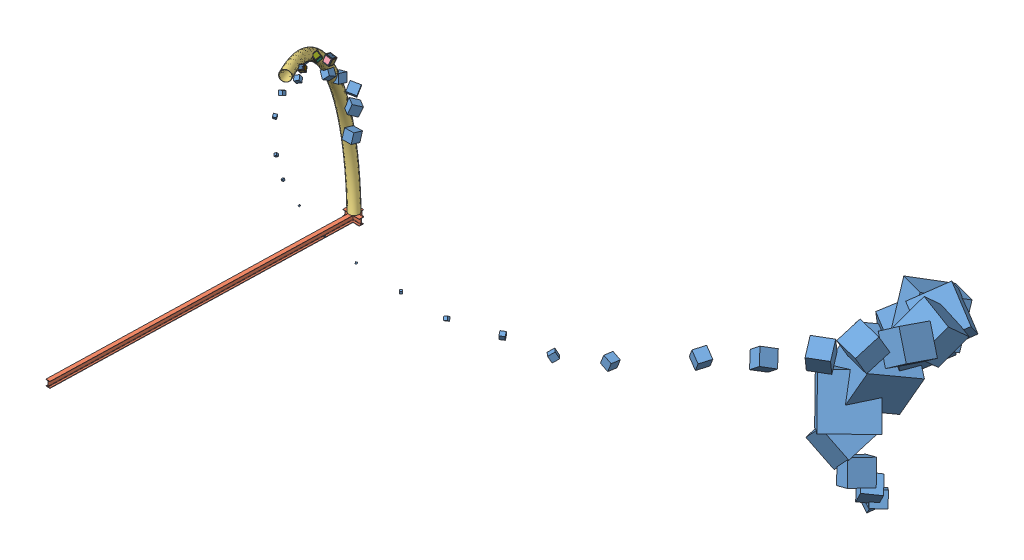
SolidWorks assembly tube4A, configuration Default. Lengths in mm.
Overall size (1783.34 3956.37 2802.08).
42 component instances, 39 part files, 12 mates.
Components (placement in the parent):
- cube_positions-1: cube_positions [Default] at (8904.7669 0 -1666.8962) x (-0.98414 0 0.177396) z (-0.177396 0 -0.98414) size (10173.18 3894.08 5705.72) (hidden)
- ground_anchor^tube4A-1: ground_anchor^tube4A [Default] at (9566.8333 -60.325 -1104.0246) x (-0.999452 0 0.033088) z (0 -1 0) size (470.34 5095.97 101.6) (hidden, virtual)
- tubes-1: tubes [tube4A] at (840.8937 1535.1212 -511.9514) x (0.194163 0.849473 0.490608) z (0.490608 -0.517175 0.701309) size (3976.83 178.46 1081.85)
- cube_06-1: cube_06 [cube06] at (471.5315 2748.7735 -1138.0748) x (0.201369 0.905147 -0.374379) z (0.964745 -0.249399 -0.084066) size (112.39 112.39 112.39)
  - panel_R^cube_06-13: panel_R^cube_06 [cube01] x (-1 0 0) z (0 0 1) size (87.38 1.59 87.38) (virtual)
  - acrylic_R^cube_06-1: acrylic_R^cube_06 [A] at origin size (109.12 3.23 109.12) (virtual)
  - panel_O^cube_06-8: panel_O^cube_06 [cube01] x (0 -1 0) z (0 0 1) size (87.38 1.59 87.38) (virtual)
  - acrylic_O^cube_06-23: acrylic_O^cube_06 [A] x (0 1 0) z (0 0 1) size (109.12 3.23 109.12) (virtual)
  - panel_Y^cube_06-9: panel_Y^cube_06 [cube01] at origin size (87.38 1.59 87.38) (virtual)
  - acrylic_Y^cube_06-24: acrylic_Y^cube_06 [A] x (-1 0 0) z (0 0 1) size (109.12 3.23 109.12) (virtual)
  - panel_G^cube_06-10: panel_G^cube_06 [cube01] x (0 1 0) z (0 0 1) size (87.38 1.59 87.38) (virtual)
  - acrylic_G^cube_06-25: acrylic_G^cube_06 [A] x (0 -1 0) z (0 0 1) size (109.12 3.23 109.12) (virtual)
  - panel_C^cube_06-11: panel_C^cube_06 [cube01] x (-1 0 0) z (0 -1 0) size (87.38 1.59 87.38) (virtual)
  - acrylic_C^cube_06-26: acrylic_C^cube_06 [B] x (1 0 0) z (0 -1 0) size (109.12 3.23 109.12) (virtual)
  - panel_B^cube_06-13: panel_B^cube_06 [cube01] x (-1 0 0) z (0 1 0) size (87.38 1.59 87.38) (virtual)
  - acrylic_B^cube_06-27: acrylic_B^cube_06 [B] x (1 0 0) z (0 1 0) size (109.12 3.23 109.12) (virtual)
- cube_07-1: cube_07 [cube07] at (645.566 3070.0096 -753.4371) x (0.234737 0.447214 -0.863075) z (0.927023 -0.370117 0.060349) size (97.16 97.16 97.16)
  - panel_R^cube_07-13: panel_R^cube_07 [cube01] x (-1 0 0) z (0 0 1) size (75.18 1.59 75.18) (virtual)
  - acrylic_R^cube_07-1: acrylic_R^cube_07 [A] at origin size (93.88 3.23 93.88) (virtual)
  - panel_O^cube_07-8: panel_O^cube_07 [cube01] x (0 -1 0) z (0 0 1) size (75.18 1.59 75.18) (virtual)
  - acrylic_O^cube_07-23: acrylic_O^cube_07 [A] x (0 1 0) z (0 0 1) size (93.88 3.23 93.88) (virtual)
  - panel_Y^cube_07-9: panel_Y^cube_07 [cube01] at origin size (75.18 1.59 75.18) (virtual)
  - acrylic_Y^cube_07-24: acrylic_Y^cube_07 [A] x (-1 0 0) z (0 0 1) size (93.88 3.23 93.88) (virtual)
  - panel_G^cube_07-10: panel_G^cube_07 [cube01] x (0 1 0) z (0 0 1) size (75.18 1.59 75.18) (virtual)
  - acrylic_G^cube_07-25: acrylic_G^cube_07 [A] x (0 -1 0) z (0 0 1) size (93.88 3.23 93.88) (virtual)
  - panel_C^cube_07-11: panel_C^cube_07 [cube01] x (-1 0 0) z (0 -1 0) size (75.18 1.59 75.18) (virtual)
  - acrylic_C^cube_07-26: acrylic_C^cube_07 [B] x (1 0 0) z (0 -1 0) size (93.88 3.23 93.88) (virtual)
  - panel_B^cube_07-13: panel_B^cube_07 [cube01] x (-1 0 0) z (0 1 0) size (75.18 1.59 75.18) (virtual)
  - acrylic_B^cube_07-27: acrylic_B^cube_07 [B] x (1 0 0) z (0 1 0) size (93.88 3.23 93.88) (virtual)
- cube_08-1: cube_08 [cube08] at (942.6163 3319.9065 -214.0269) x (-0.520827 0.525094 -0.673064) z (0.853659 0.322603 -0.408894) size (81.92 81.92 81.92)
  - panel_R^cube_08-13: panel_R^cube_08 [cube01] x (-1 0 0) z (0 0 1) size (62.99 1.59 62.99) (virtual)
  - acrylic_R^cube_08-1: acrylic_R^cube_08 [A] at origin size (78.64 3.23 78.64) (virtual)
  - panel_O^cube_08-8: panel_O^cube_08 [cube01] x (0 -1 0) z (0 0 1) size (62.99 1.59 62.99) (virtual)
  - acrylic_O^cube_08-23: acrylic_O^cube_08 [A] x (0 1 0) z (0 0 1) size (78.64 3.23 78.64) (virtual)
  - panel_Y^cube_08-9: panel_Y^cube_08 [cube01] at origin size (62.99 1.59 62.99) (virtual)
  - acrylic_Y^cube_08-24: acrylic_Y^cube_08 [A] x (-1 0 0) z (0 0 1) size (78.64 3.23 78.64) (virtual)
  - panel_G^cube_08-10: panel_G^cube_08 [cube01] x (0 1 0) z (0 0 1) size (62.99 1.59 62.99) (virtual)
  - acrylic_G^cube_08-25: acrylic_G^cube_08 [A] x (0 -1 0) z (0 0 1) size (78.64 3.23 78.64) (virtual)
  - panel_C^cube_08-11: panel_C^cube_08 [cube01] x (-1 0 0) z (0 -1 0) size (62.99 1.59 62.99) (virtual)
  - acrylic_C^cube_08-26: acrylic_C^cube_08 [B] x (1 0 0) z (0 -1 0) size (78.64 3.23 78.64) (virtual)
  - panel_B^cube_08-13: panel_B^cube_08 [cube01] x (-1 0 0) z (0 1 0) size (62.99 1.59 62.99) (virtual)
  - acrylic_B^cube_08-27: acrylic_B^cube_08 [B] x (1 0 0) z (0 1 0) size (78.64 3.23 78.64) (virtual)
Mates (geometry in assembly coordinates):
- Lock1: lock: unknown of assembly; unknown of ?
- Coincident1: coincident anti-aligned: plane of ground_anchor^tube4A-1 through (449.1246 0 3216.5534) normal (0 -1 0); plane of assembly through (0 0 0) normal (0 1 0)
- Coincident2: coincident aligned: plane of cube_positions-1 through (290.8601 2818.3314 -1040.6765) normal (-0.964745 0.249399 0.084066); plane of cube_06-1/panel_B^cube_06-13 through (273.0562 2780.0027 -1131.2857) normal (-0.964745 0.249399 0.084066)
- Coincident3: coincident aligned: plane of cube_positions-1 through (391.4267 2792.3336 -1049.4396) normal (0.169461 0.344252 0.923457); plane of cube_06-1/panel_R^cube_06-13 through (302.0514 2811.2686 -1040.0973) normal (0.169461 0.344252 0.923457)
- Coincident4: coincident aligned: plane of cube_positions-1 through (352.7707 2662.0943 -1106.6765) normal (-0.201369 -0.905147 0.374379); plane of cube_06-1/panel_O^cube_06-8 through (279.8176 2716.5511 -1014.2543) normal (-0.201369 -0.905147 0.374379)
- Coincident5: coincident aligned: plane of cube_positions-1 through (529.5721 2928.2446 -651.0495) normal (-0.234737 -0.447214 0.863075); plane of cube_07-1/panel_O^cube_07-8 through (472.6851 3024.1588 -616.8223) normal (-0.234737 -0.447214 0.863075)
- Coincident6: coincident aligned: plane of cube_positions-1 through (555.7789 3001.2111 -606.1133) normal (0.29245 0.814257 0.501457); plane of cube_07-1/panel_R^cube_07-13 through (496.1249 3071.64 -685.6843) normal (0.29245 0.814257 0.501457)
- Coincident7: coincident aligned: plane of cube_positions-1 through (529.5721 2928.2446 -651.0495) normal (0.927023 -0.370117 0.060349); plane of cube_07-1/panel_C^cube_07-11 through (572.7933 3030.8022 -685.9928) normal (0.927023 -0.370117 0.060349)
- Coincident8: coincident aligned: plane of cube_positions-1 through (958.6365 3187.3449 -144.6636) normal (0.520827 -0.525094 0.673064); plane of cube_08-1/panel_O^cube_08-8 through (896.5032 3255.773 -43.1995) normal (0.520827 -0.525094 0.673064)
- Coincident9: coincident aligned: plane of cube_positions-1 through (958.6365 3187.3449 -144.6636) normal (0.853659 0.322603 -0.408894); plane of cube_08-1/panel_C^cube_08-11 through (920.9236 3217.9385 -199.2603) normal (0.853659 0.322603 -0.408894)
- Coincident10: coincident aligned: plane of cube_positions-1 through (894.6285 3163.1558 -114.0044) normal (-0.002425 0.78753 0.616271); plane of ? through (859.0501 3202.016 -163.8037) normal (-0.002425 0.78753 0.616271)
- cube placement: unknown: unknown of ?; unknown of ?; unknown of ?; unknown of cube_07-1/acrylic_B^cube_07-27; unknown of ?; unknown of ?; unknown of cube_06-1/acrylic_B^cube_06-27; unknown of ?; unknown of ?; unknown of cube_08-1/acrylic_B^cube_08-27; unknown of tubes-1; unknown of tubes-1
